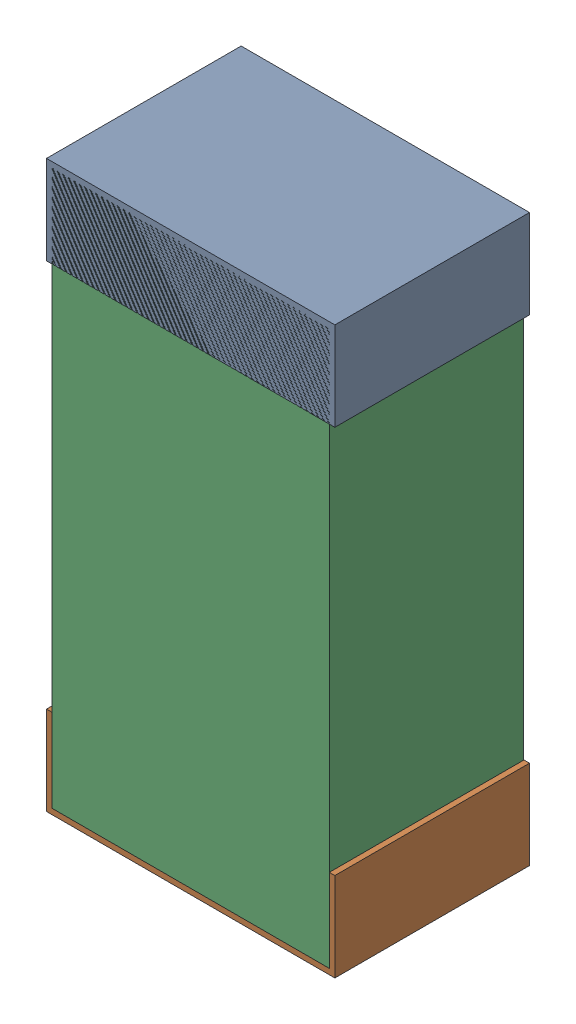
SolidWorks assembly C58, configuration Default. Lengths in mm.
Overall size (0.52 1.02 0.35).
6 component instances, 2 part files, 0 mates.
Components (placement in the parent):
- 870941120-1: 870941120 [Default] at (19.9382 31.3866 -1.9516) size (0.52 0.16 0.35)
  - Extruded_3-1: Extruded_3 [Default] at origin size (0.52 0.16 0.35)
- 870941120-2: 870941120 [Default] at (19.9382 30.5266 -1.9516) size (0.52 0.16 0.35)
  - Extruded_3-1: Extruded_3 [Default] at origin size (0.52 0.16 0.35)
- 870941280-1: 870941280 [Default] at (19.9382 30.9566 -1.9506) size (0.5 1 0.35)
  - Extruded_4-1: Extruded_4 [Default] at origin size (0.5 1 0.35)
